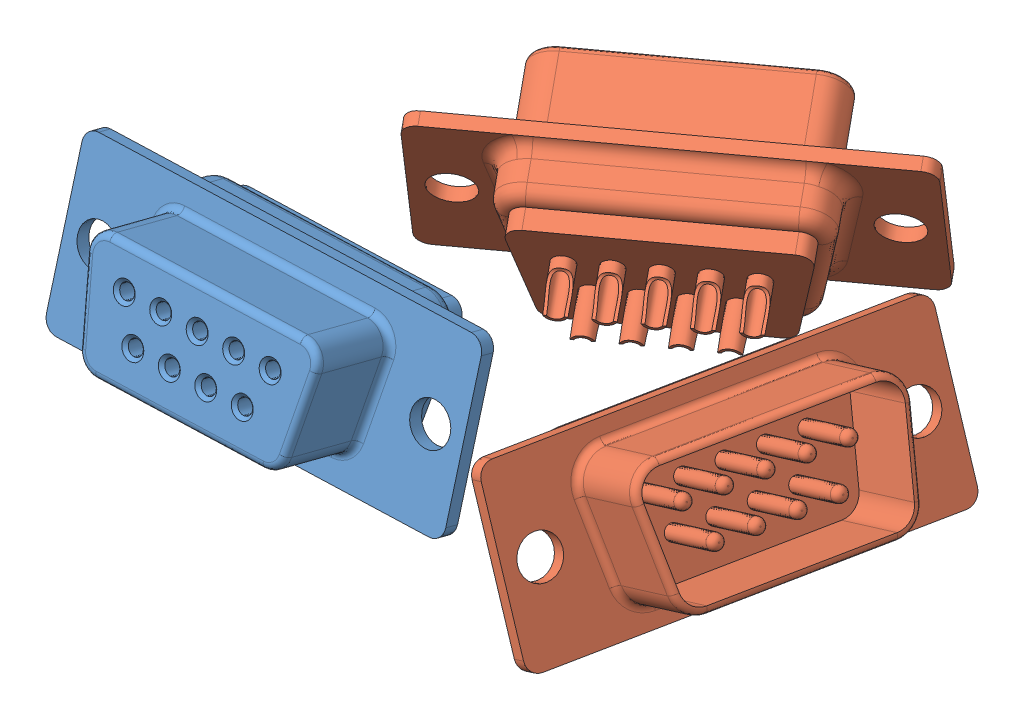
SolidWorks assembly DB-9, configuration По умолчанию. Lengths in mm.
Overall size (54.58 17.62 49.27).
3 component instances, 2 part files, 4 mates.
Components (placement in the parent):
- COM DB-9 female-1: COM DB-9 female [По умолчанию] at (-9.7678 6.1487 2.8993) x (0.999351 0 -0.036012) z (0.03464 0.273342 0.961293) size (30 12.5 15.41)
- COM DB-9 male-1: COM DB-9 male [По умолчанию] at (18.216 6.3243 -4.5062) x (0.196392 0 -0.980525) z (0.898666 0.4 0.179997) size (30 12.5 15.41)
- COM DB-9 male-2: COM DB-9 male [По умолчанию] at (-2.6726 6.3243 -21.7309) x (-0.807562 0 0.589783) z (-0.540545 0.4 -0.740142) size (30 12.5 15.41)
Mates (geometry in assembly coordinates):
- Касательность2: tangent anti-aligned: cylinder of COM DB-9 male-1 through (16.0417 1 1.5149) axis (0.196392 0 -0.980525) radius 1; plane of assembly through (0 0 0) normal (0 1 0)
- Совпадение3: coincident: line of COM DB-9 male-1 through (16.2817 0 -11.3502) axis (-0.196392 0 0.980525); plane of assembly
- Касательность3: tangent anti-aligned: cylinder of COM DB-9 male-2 through (2.9999 1 -24.6979) axis (-0.807562 0 0.589783) radius 1; plane of assembly through (0 0 0) normal (0 1 0)
- Совпадение4: coincident: line of COM DB-9 male-2 through (-5.8738 0 -15.3799) axis (0.807562 0 -0.589783); plane of assembly
